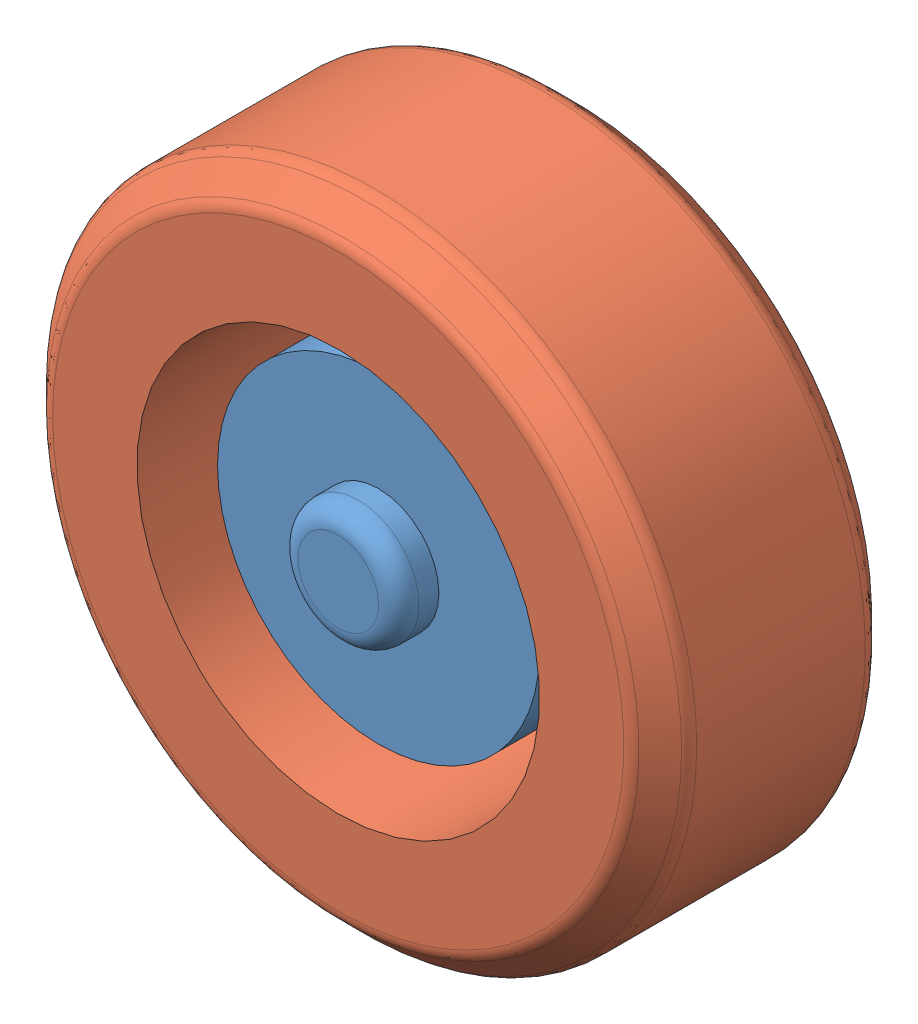
SolidWorks assembly wheel, configuration Default. Lengths in mm.
Overall size (571.71 571.71 152.4).
2 component instances, 2 part files, 0 mates.
Components (placement in the parent):
- wheel-1-1: wheel-1 [Default] at origin size (203.2 203.2 101.6)
- tire-1-1: tire-1 [Default] at (0 0 -25.4) x (0.775855 -0.630912 0) z (0 0 1) size (406.4 406.4 152.4)
